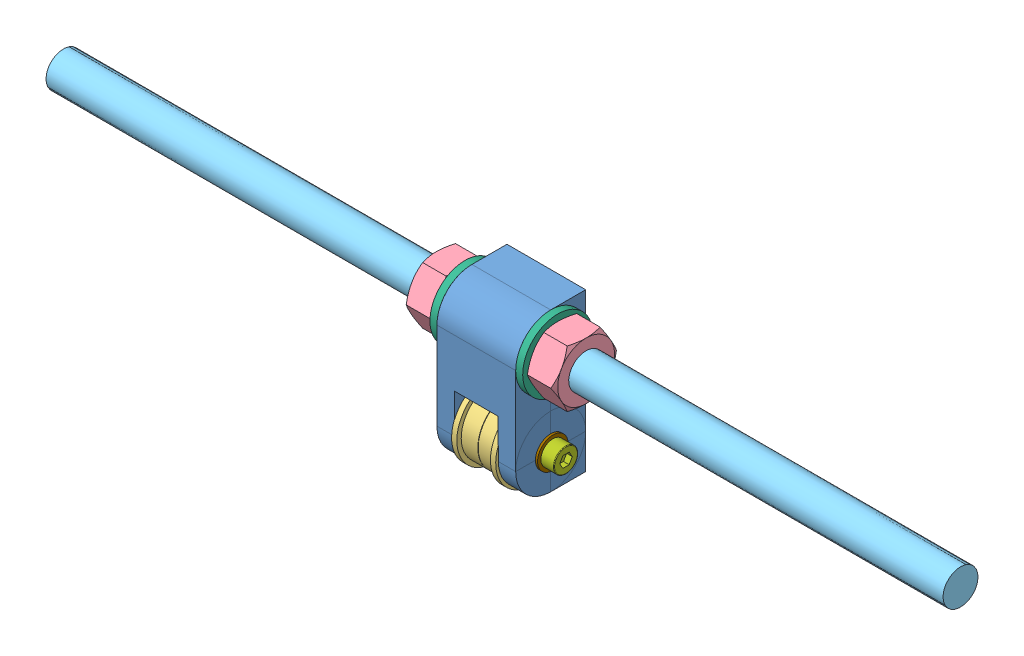
SolidWorks assembly Assembly y-axis front side, configuration Valor predeterminado. Lengths in mm.
Overall size (205 43.44 24.25).
14 component instances, 9 part files, 26 mates.
Components (placement in the parent):
- y-idler-1: y-idler [Valor predeterminado] at (9 -20 0) size (18 36 16)
- Assembly belt-guide + bearing-1: Assembly belt-guide + bearing [Valor predeterminado] at (0 -20 8) size (10.08 24.25 24.25)
  - Radial ball bearing DIN 625 - 623-1: Radial ball bearing DIN 625 - 623 [Valor predeterminado] at origin size (4 10 10)
  - belt-guide-1: belt-guide [Valor predeterminado] at (5.04 0 0) x (0 -0.638719 0.76944) z (-1 0 0) size (17.22 17.22 5)
  - belt-guide-2: belt-guide [Valor predeterminado] at (-5.04 0 0) x (0 -0.984931 0.17295) z (1 0 0) size (17.22 17.22 5)
- Nut DIN 934 - M8-1: Nut DIN 934 - M8 [Valor predeterminado] at (13.85 0 8) size (6.5 13 15.01)
- Threaded Rod DIN 975 - M8 x 205-1: Threaded Rod DIN 975 - M8 x 205 [Valor predeterminado] at (0.156 0 8) x (0 -0.74578 -0.666192) z (-1 0 0) size (8 8 205)
- Washer DIN 125A - M8-1: Washer DIN 125A - M8 [Valor predeterminado] at (9 0 8) x (1 0 0) z (0 0.918544 0.39532) size (1.6 16 16)
- Washer DIN 125A - M8-2: Washer DIN 125A - M8 [Valor predeterminado] at (-10.6 0 8) x (1 0 0) z (0 0.699031 0.715091) size (1.6 16 16)
- Nut DIN 934 - M8-2: Nut DIN 934 - M8 [Valor predeterminado] at (-13.85 0 8) x (1 0 0) z (0 0.866025 0.5) size (6.5 13 15.01)
- Screw DIN 912 - M3 x 25 --- 18N-1: Screw DIN 912 - M3 x 25 --- 18N [Valor predeterminado] at (12.5 -20 8) size (28 5.5 5.5)
- Nut DIN 985 - M3-1: Nut DIN 985 - M3 [Valor predeterminado] at (-9.5 -20 8) x (1 0 0) z (0 0.5 0.866025) size (4 6.35 5.5)
- Washer DIN 125A - M3-1: Washer DIN 125A - M3 [Valor predeterminado] at (9 -20 8) x (1 0 0) z (0 -0.048044 0.998845) size (0.5 7 7)
- Washer DIN 125A - M3-2: Washer DIN 125A - M3 [Valor predeterminado] at (-9.5 -20 8) x (1 0 0) z (0 -0.314993 0.949094) size (0.5 7 7)
Mates (geometry in assembly coordinates):
- Concêntrico1: concentric: cylinder of ? through (-36.3916 -20 8) axis (-1 0 0) radius 1.8; cylinder of ? through (7.2095 -20 8) axis (1 0 0) radius 1.5
- Concêntrico2: concentric: cylinder of ? through (-36.3916 0 8) axis (-1 0 0) radius 4.5; cylinder of ? through (-35.7916 0 8) axis (-1 0 0) radius 4.2
- Coincidente2: coincident: plane of ? through (-37.3916 0 8) normal (1 0 0); plane of ? through (-37.3916 0 8) normal (-1 0 0)
- Concêntrico3: concentric: cylinder of ? through (-36.3916 0 8) axis (-1 0 0) radius 4.5; cylinder of ? through (-29.2916 0 8) axis (-1 0 0) radius 3.4
- Coincidente3: coincident: plane of ? through (-35.7916 0 0.4944) normal (-1 0 0); plane of ? through (-35.7916 0 8) normal (1 0 0)
- Paralelo1: parallel: plane of ? through (-37.3916 8 0) normal (0 1 0); plane of ? through (-29.2916 6.5 4.2472) normal (0 1 0)
- Concêntrico4: concentric: cylinder of ? through (-36.3916 0 8) axis (-1 0 0) radius 4.5; cylinder of Threaded Rod DIN 975 - M8 x 205-1 through (-102.344 0 8) axis (1 0 0) radius 4
- Concêntrico5: concentric: cylinder of ? through (-36.3916 0 8) axis (-1 0 0) radius 4.5; cylinder of ? through (-55.3916 0 8) axis (-1 0 0) radius 4.2
- Coincidente6: coincident: plane of ? through (-55.3916 0 8) normal (-1 0 0); plane of ? through (-55.3916 0 8) normal (1 0 0)
- Concêntrico6: concentric: cylinder of ? through (-36.3916 0 8) axis (-1 0 0) radius 4.5; cylinder of ? through (-56.9916 0 8) axis (-1 0 0) radius 3.4
- Coincidente7: coincident: plane of ? through (-56.9916 0 8) normal (-1 0 0); plane of ? through (-56.9916 -6.5 4.2472) normal (1 0 0)
- Paralelo2: parallel: plane of ? through (-37.3916 8 0) normal (0 1 0); plane of ? through (-56.9916 6.5 4.2472) normal (0 1 0)
- Concêntrico8: concentric: cylinder of ? through (-36.3916 -20 8) axis (-1 0 0) radius 1.8; cylinder of ? through (-36.8916 -20 8) axis (-1 0 0) radius 1.6
- Coincidente12: coincident: plane of ? through (-37.3916 -20 8) normal (1 0 0); plane of ? through (-37.3916 -20 8) normal (-1 0 0)
- Concêntrico9: concentric: cylinder of ? through (-36.3916 -20 8) axis (-1 0 0) radius 1.8; cylinder of ? through (-33.8916 -20 8) axis (1 0 0) radius 1.5
- Coincidente13: coincident: plane of ? through (-36.8916 -17.25 8) normal (-1 0 0); plane of ? through (-36.8916 -20 8) normal (1 0 0)
- Concêntrico10: concentric: cylinder of ? through (-33.8916 -20 8) axis (1 0 0) radius 1.5; cylinder of ? through (-55.3916 -20 8) axis (-1 0 0) radius 1.6
- Coincidente14: coincident: plane of ? through (-55.3916 -20 8) normal (-1 0 0); plane of ? through (-55.3916 -20 8) normal (1 0 0)
- Concêntrico11: concentric: cylinder of ? through (-33.8916 -20 8) axis (1 0 0) radius 1.5; cylinder of ? through (-64.0136 -20 8) axis (-1 0 0) radius 1.25
- Coincidente15: coincident: plane of ? through (-55.8916 -20 8) normal (1 0 0); plane of ? through (-55.8916 -20 8) normal (-1 0 0)
- Paralelo3: parallel: plane of ? through (-37.3916 8 0) normal (0 1 0); plane of ? through (-59.8916 -17.25 6.4123) normal (0 1 0)
- Coincidente16: coincident: plane of ? through (-37.3916 -28 0) normal (0 0 -1); plane of assembly through (0 0 0) normal (0 0 1)
- Coincidente17: coincident: line of assembly; line of Threaded Rod DIN 975 - M8 x 205-1 through (-102.344 0 8) axis (1 0 0); plane of assembly
- Paralelo4: parallel: plane of ? through (27.847 -20 8) normal (0 0 1)
- Simétrico1: symmetric: plane of assembly; plane of assembly; plane of y-idler-1 through (5 -20 8) normal (-1 0 0); plane of y-idler-1 through (-5 -20 8) normal (1 0 0); plane of assembly
- Coincidente19: coincident: plane of Assembly belt-guide + bearing-1/Radial ball bearing DIN 625 - 623-1 through (0 -20 8) normal (1 0 0)
